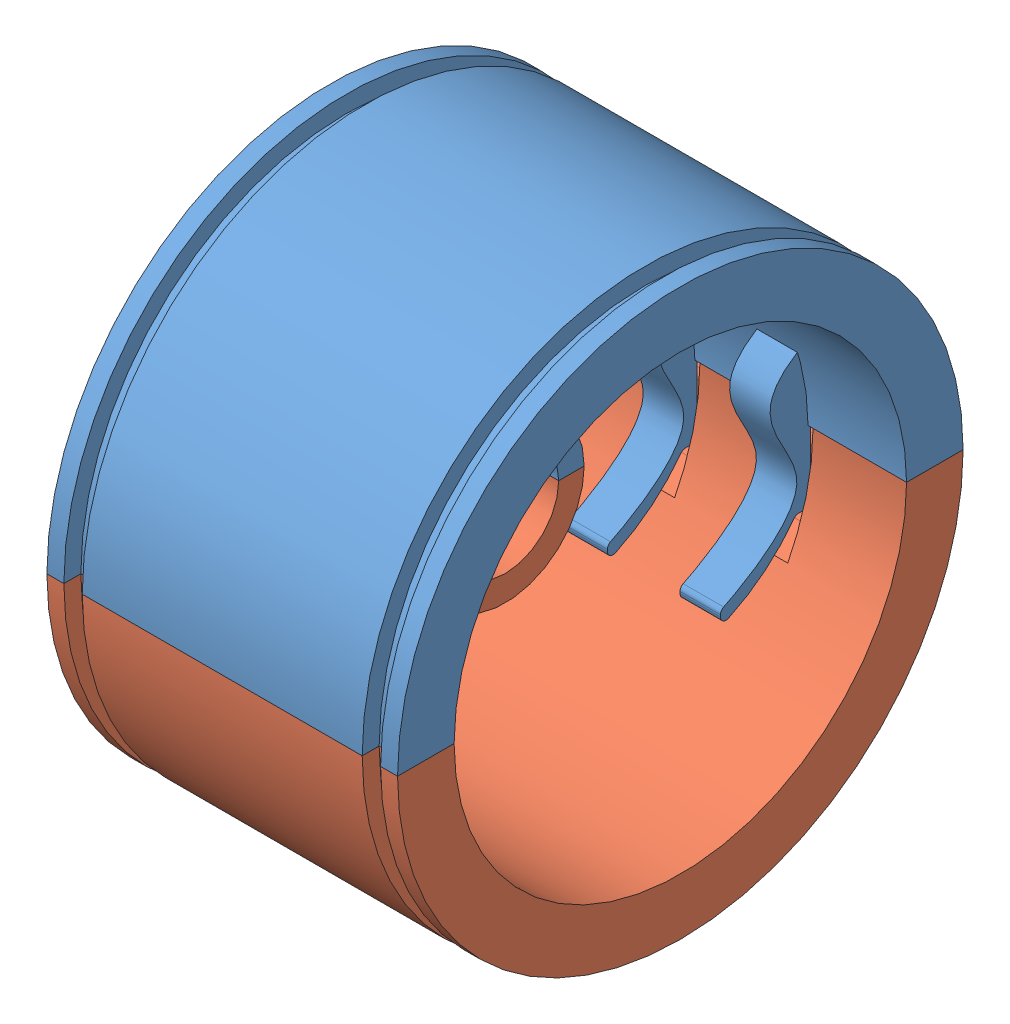
SolidWorks assembly assembly_half, configuration Default. Lengths in mm.
Overall size (171.63 102.25 111.02).
2 component instances, 2 part files, 2 mates.
Components (placement in the parent):
- half_1-1: half_1 [Default] at (32.6158 54.5109 77.6649) size (67.93 72.58 100)
- half_2-1: half_2 [Default] at (32.6158 54.5109 77.6649) x (1 0 0) z (0 0 -1) size (171.63 59.41 111.02)
Mates (geometry in assembly coordinates):
- Coincident4: coincident aligned: plane of half_1-1 through (63.6158 54.5109 127.6649) normal (1 0 0); plane of half_2-1 through (63.6158 54.5109 27.6649) normal (1 0 0)
- Coincident5: coincident anti-aligned: plane of half_1-1 through (0.4388 54.5109 59.643) normal (0 -1 0); plane of half_2-1 through (0.4388 54.5109 59.643) normal (0 1 0)
